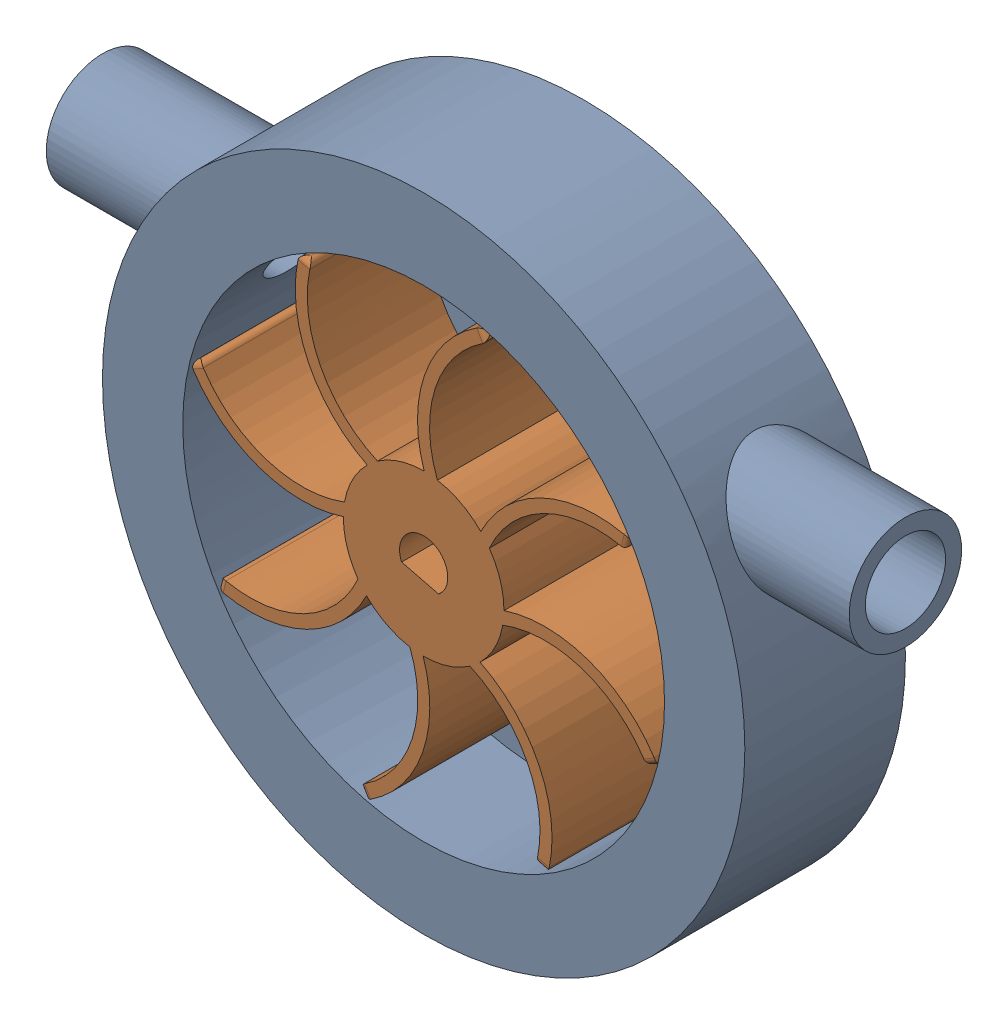
SolidWorks assembly Assem bomba antiga fred, configuration Default. Lengths in mm.
Overall size (100 80 20).
2 component instances, 2 part files, 2 mates.
Components (placement in the parent):
- Bomba anterior aumentada ´fred-1: Bomba anterior aumentada ´fred [Default] at (2.8427 -4.0809 1.2725) size (100 80 20)
- helice 3 fred-1: helice 3 fred [Default] at (2.8427 -4.0809 -13.7275) x (0.970447 -0.241314 0) z (0 0 1) size (59.35 59.35 15)
Mates (geometry in assembly coordinates):
- Concentric1: concentric aligned: circle of Bomba anterior aumentada ´fred-1; circle of helice 3 fred-1
- Coincident1: coincident anti-aligned: plane of Bomba anterior aumentada ´fred-1 through (2.8427 -4.0809 -13.7275) normal (0 0 1); plane of helice 3 fred-1 through (2.8427 -4.0809 -13.7275) normal (0 0 -1)
